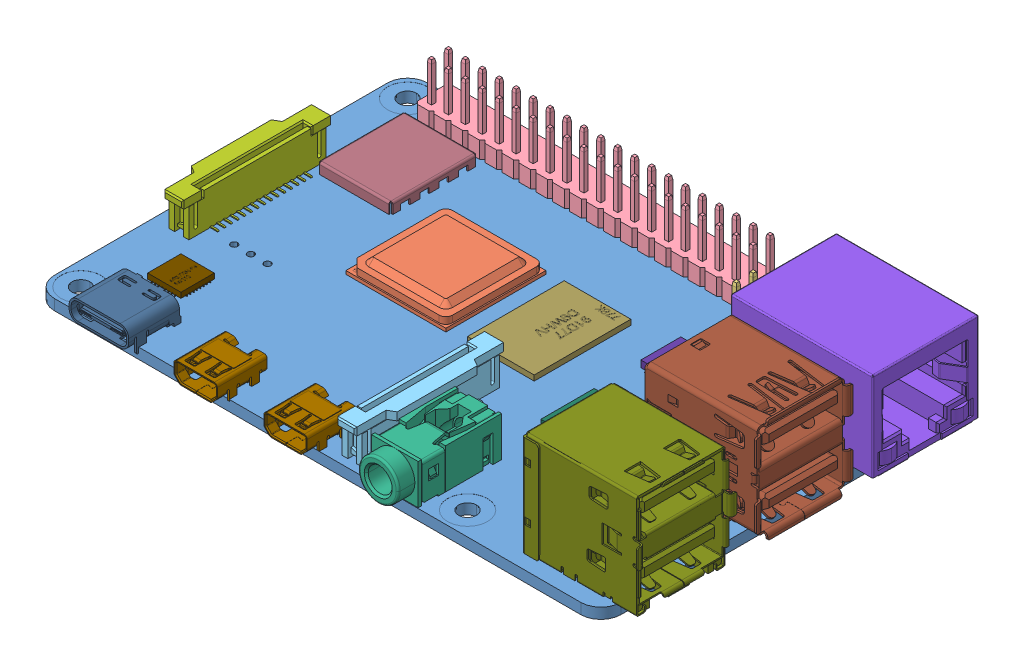
SolidWorks assembly Rasp avec chassis, configuration Défaut. Lengths in mm.
Overall size (89 19.92 58.4).
20 component instances, 18 part files, 0 mates.
Components (placement in the parent):
- Raspberry Pi 4 Model B.STEP-1: Raspberry Pi 4 Model B.STEP [Défaut] at (-12.1485 20.5809 35.8734) size (89 19.92 58.4)
  - PCB, RPi4ModelB.STEP-1: PCB, RPi4ModelB.STEP [Défaut] at origin size (85 1.6 56)
  - Broadcom BCM2711B0 CPU, RPi4ModelB.STEP-1: Broadcom BCM2711B0 CPU, RPi4ModelB.STEP [Défaut] at (-13.25 0.8 -4.5) size (15 2.3 15)
  - 2.54 mm DUPONT MALE PIN HEADER, POE, 2X2, RPi4ModelB.STEP-1: 2.54 mm DUPONT MALE PIN HEADER, POE, 2X2, RPi4ModelB.STEP [Défaut] at (19 0.8 -18.36) size (5.08 11.3 5.08)
  - 2.54 mm DUPONT MALE PIN HEADER, IO, 2X20, RPi4ModelB.STEP-1: 2.54 mm DUPONT MALE PIN HEADER, IO, 2X20, RPi4ModelB.STEP [Défaut] at (-10 0.8 -24.5) size (50.8 11.3 5.08)
  - Camera Connector, RPi4ModelB.STEP-1: Camera Connector, RPi4ModelB.STEP [Défaut] at (4 0.8 16.5) x (0 0 -1) z (1 0 0) size (22.4 5.68 5.07)
  - Microphone Plug, RPi4ModelB.STEP-1: Microphone Plug, RPi4ModelB.STEP [Défaut] at (11.5 0.8 21.65) size (7.23 7.55 15)
  - Display Connector, RPi4ModelB.STEP-1: Display Connector, RPi4ModelB.STEP [Défaut] at (-38.5 0.8 0) x (0 0 1) z (-1 0 0) size (22.4 5.68 5.07)
  - Gigabit Ethernet Port, RPi4ModelB.STEP-1: Gigabit Ethernet Port, RPi4ModelB.STEP [Défaut] at (45.5 7.55 -17.75) x (0 0 -1) z (1 0 0) size (16.33 17.24 21.6)
  - Female Micro HDMI Connector, RPi4ModelB.STEP-1: Female Micro HDMI Connector, RPi4ModelB.STEP [Défaut] at (-3 0.8 27.3875) size (6.5 3.51 7.5)
  - Female Micro HDMI Connector, RPi4ModelB.STEP-2: Female Micro HDMI Connector, RPi4ModelB.STEP [Défaut] at (-16.5 0.8 27.3875) size (6.5 3.51 7.5)
  - Female USB Type C Connector, RPi4ModelB.STEP-1: Female USB Type C Connector, RPi4ModelB.STEP [Défaut] at (-31.3 0.8 26.5419) size (8.94 3.96 7.9)
  - 2X USB3.0 PORTS, RPi4ModelB.STEP-1: 2X USB3.0 PORTS, RPi4ModelB.STEP [Défaut] at (37.07 0.8 1) size (17.48 19.42 15.69)
  - 91D77 D9WHV 778K, 4 GB LPDDR4 SDRAM, RPi4ModelB.STEP-1: 91D77 D9WHV 778K, 4 GB LPDDR4 SDRAM, RPi4ModelB.STEP [Défaut] at (2.25 0.8 -4.5) size (10 0.8 14.5)
  - Cypress CYW43455 Wireless Module Cover, RPi4ModelB.STEP-1: Cypress CYW43455 Wireless Module Cover, RPi4ModelB.STEP [Défaut] at (-30.5 0.8 -14.5) size (11 1.6 13)
  - SD Card Slot, RPi4ModelB.STEP-1: SD Card Slot, RPi4ModelB.STEP [Défaut] at (-35.3 -0.8 0) x (0 0 -1) z (-1 0 0) size (11.95 1.45 11.4)
  - VIA VL805 PCIe USB 3.0 controller, RPi4ModelB.STEP-1: VIA VL805 PCIe USB 3.0 controller, RPi4ModelB.STEP [Défaut] at (17.5 0.8 4) size (8.8 0.8 8.8)
  - 2X USB2.0 PORTS, RPi4ModelB.STEP-1: 2X USB2.0 PORTS, RPi4ModelB.STEP [Défaut] at (37.065 0.65 19) size (17.87 19.17 15.35)
  - Broadcom BCM54213PE Gigabit Ethernet Transceiver, RPi4ModelB.STEP-1: Broadcom BCM54213PE Gigabit Ethernet Transceiver, RPi4ModelB.STEP [Défaut] at (16.5 0.8 -10) size (6.8 1 6.8)
  - MxL7704 Universal PMIC, RPi4ModelB.STEP-1: MxL7704 Universal PMIC, RPi4ModelB.STEP [Défaut] at (-32.5 0.8 16) size (5.4 0.8 5.4)
